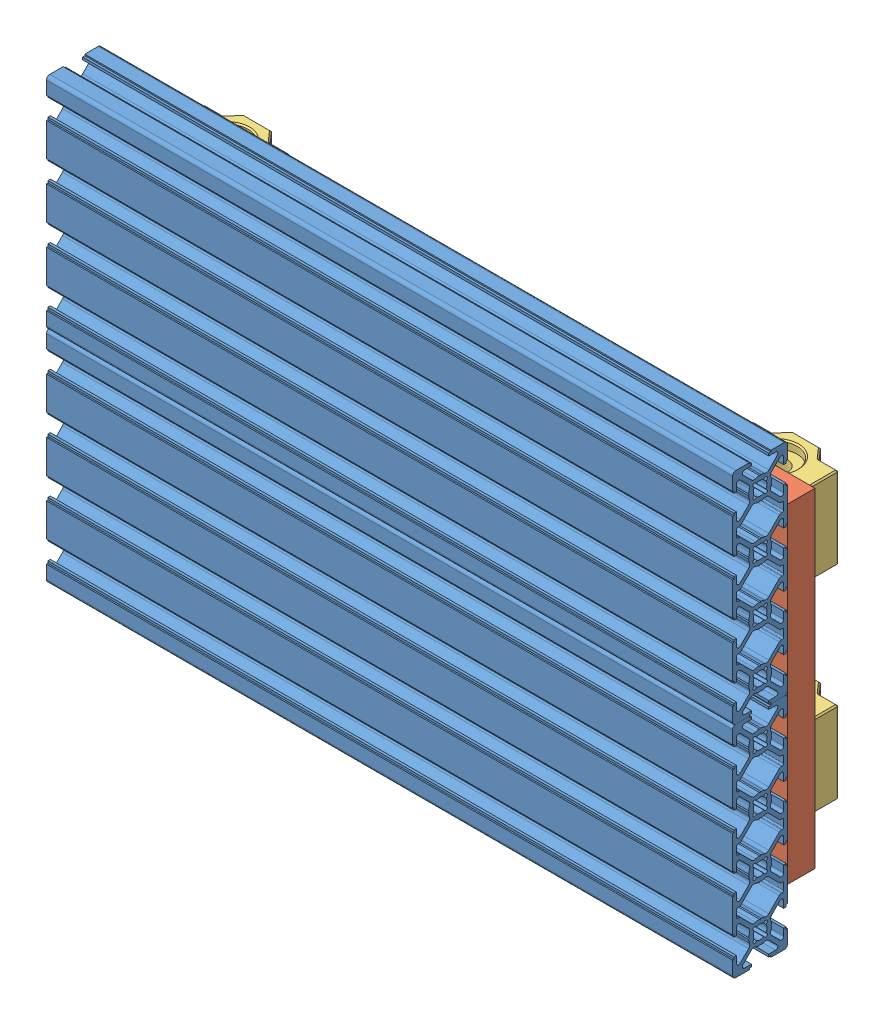
SolidWorks assembly AXIS_Y_DYNAMIC-but_bigger, configuration Default. Lengths in mm.
Overall size (250 160 52.8).
40 component instances, 6 part files, 77 mates.
Components (placement in the parent):
- 20x80x250_surface-1: 20x80x250_surface [Varsayılan] at (125 -70 0) x (0 1 0) z (1 0 0) size (80 20 250)
- 20x80x250_surface-2: 20x80x250_surface [Varsayılan] at (125 10 0) x (0 1 0) z (1 0 0) size (80 20 250)
- y_axis_elevation-1: y_axis_elevation [Default] at (100 0 -20) x (0 1 0) z (1 0 0) size (120 10 50)
- y_axis_elevation-3: y_axis_elevation [Default] at (-100 0 -20) x (0 1 0) z (1 0 0) size (120 10 50)
- linear_bearing_caged-5: linear_bearing_caged [Default] at (100 37 -31) x (1 0 0) z (0 1 0) size (34 22 30)
- linear_bearing_caged-6: linear_bearing_caged [Default] at (100 -37 -31) x (1 0 0) z (0 1 0) size (34 22 30)
- linear_bearing_caged-7: linear_bearing_caged [Default] at (-100 37 -31) x (1 0 0) z (0 1 0) size (34 22 30)
- linear_bearing_caged-8: linear_bearing_caged [Default] at (-100 -37 -31) x (1 0 0) z (0 1 0) size (34 22 30)
- socket head cap screw_din-2: socket head cap screw_din [DIN 912 M4 x 16 --- 16N] at (112 46 -10) x (0 0 -1) z (1 0 0) size (20 7 7)
- socket head cap screw_din-3: socket head cap screw_din [DIN 912 M4 x 16 --- 16N] at (88 46 -10) x (0 0 -1) z (1 0 0) size (20 7 7)
- socket head cap screw_din-4: socket head cap screw_din [DIN 912 M4 x 16 --- 16N] at (88 28 -10) x (0 0 -1) z (1 0 0) size (20 7 7)
- socket head cap screw_din-5: socket head cap screw_din [DIN 912 M4 x 16 --- 16N] at (112 28 -10) x (0 0 -1) z (1 0 0) size (20 7 7)
- socket head cap screw_din-6: socket head cap screw_din [DIN 912 M4 x 16 --- 16N] at (112 -28 -10) x (0 0 -1) z (1 0 0) size (20 7 7)
- socket head cap screw_din-7: socket head cap screw_din [DIN 912 M4 x 16 --- 16N] at (88 -28 -10) x (0 0 -1) z (1 0 0) size (20 7 7)
- socket head cap screw_din-8: socket head cap screw_din [DIN 912 M4 x 16 --- 16N] at (88 -46 -10) x (0 0 -1) z (1 0 0) size (20 7 7)
- socket head cap screw_din-9: socket head cap screw_din [DIN 912 M4 x 16 --- 16N] at (112 -46 -10) x (0 0 -1) z (1 0 0) size (20 7 7)
- socket head cap screw_din-10: socket head cap screw_din [DIN 912 M4 x 16 --- 16N] at (-112 46 -10) x (0 0 -1) z (1 0 0) size (20 7 7)
- socket head cap screw_din-11: socket head cap screw_din [DIN 912 M4 x 16 --- 16N] at (-88 46 -10) x (0 0 -1) z (1 0 0) size (20 7 7)
- socket head cap screw_din-12: socket head cap screw_din [DIN 912 M4 x 16 --- 16N] at (-88 28 -10) x (0 0 -1) z (1 0 0) size (20 7 7)
- socket head cap screw_din-13: socket head cap screw_din [DIN 912 M4 x 16 --- 16N] at (-112 28 -10) x (0 0 -1) z (1 0 0) size (20 7 7)
- socket head cap screw_din-14: socket head cap screw_din [DIN 912 M4 x 16 --- 16N] at (-88 -28 -10) x (0 0 -1) z (1 0 0) size (20 7 7)
- socket head cap screw_din-15: socket head cap screw_din [DIN 912 M4 x 16 --- 16N] at (-112 -28 -10) x (0 0 -1) z (1 0 0) size (20 7 7)
- socket head cap screw_din-16: socket head cap screw_din [DIN 912 M4 x 16 --- 16N] at (-112 -46 -10) x (0 0 -1) z (1 0 0) size (20 7 7)
- socket head cap screw_din-17: socket head cap screw_din [DIN 912 M4 x 16 --- 16N] at (-88 -46 -10) x (0 0 -1) z (1 0 0) size (20 7 7)
- socket head cap screw_din-19: socket head cap screw_din [DIN 912 M5 x 10 --- 10N] at (100 50 -20) x (0 0 1) z (-1 0 0) size (15 8.5 8.5)
- socket head cap screw_din-20: socket head cap screw_din [DIN 912 M5 x 10 --- 10N] at (100 30 -20) x (0 0 1) z (-1 0 0) size (15 8.5 8.5)
- socket head cap screw_din-21: socket head cap screw_din [DIN 912 M5 x 10 --- 10N] at (100 10 -20) x (0 0 1) z (-1 0 0) size (15 8.5 8.5)
- socket head cap screw_din-22: socket head cap screw_din [DIN 912 M5 x 10 --- 10N] at (100 -10 -20) x (0 0 1) z (-1 0 0) size (15 8.5 8.5)
- socket head cap screw_din-23: socket head cap screw_din [DIN 912 M5 x 10 --- 10N] at (100 -30 -20) x (0 0 1) z (-1 0 0) size (15 8.5 8.5)
- socket head cap screw_din-24: socket head cap screw_din [DIN 912 M5 x 10 --- 10N] at (100 -50 -20) x (0 0 1) z (-1 0 0) size (15 8.5 8.5)
- socket head cap screw_din-25: socket head cap screw_din [DIN 912 M5 x 10 --- 10N] at (-100 50 -20) x (0 0 1) z (-1 0 0) size (15 8.5 8.5)
- socket head cap screw_din-26: socket head cap screw_din [DIN 912 M5 x 10 --- 10N] at (-100 30 -20) x (0 0 1) z (-1 0 0) size (15 8.5 8.5)
- socket head cap screw_din-27: socket head cap screw_din [DIN 912 M5 x 10 --- 10N] at (-100 10 -20) x (0 0 1) z (-1 0 0) size (15 8.5 8.5)
- socket head cap screw_din-28: socket head cap screw_din [DIN 912 M5 x 10 --- 10N] at (-100 -10 -20) x (0 0 1) z (-1 0 0) size (15 8.5 8.5)
- socket head cap screw_din-29: socket head cap screw_din [DIN 912 M5 x 10 --- 10N] at (-100 -30 -20) x (0 0 1) z (-1 0 0) size (15 8.5 8.5)
- socket head cap screw_din-30: socket head cap screw_din [DIN 912 M5 x 10 --- 10N] at (-100 -50 -20) x (0 0 1) z (-1 0 0) size (15 8.5 8.5)
- SK10_rod_holder-1: SK10_rod_holder [Default] at (0 3 -30) x (1 0 0) z (0 1 0) size (42 32.8 14)
- trapezoidal_nut-1: trapezoidal_nut [Default] at (0 21 -30) x (0.995058 0 0.099296) z (0 -1 0) size (22 22 15)
- socket head cap screw_din-31: socket head cap screw_din [DIN 912 M5 x 10 --- 10N] at (16 10 -21) x (0 0 1) z (-1 0 0) size (15 8.5 8.5)
- socket head cap screw_din-32: socket head cap screw_din [DIN 912 M5 x 10 --- 10N] at (-16 10 -21) x (0 0 1) z (-1 0 0) size (15 8.5 8.5)
Mates (geometry in assembly coordinates):
- Coincident1: coincident anti-aligned: plane of 20x80x250_surface-1 through (-125 0 3.95) normal (0 1 0); plane of 20x80x250_surface-2 through (-125 0 8.8) normal (0 -1 0)
- Coincident2: coincident aligned: plane of 20x80x250_surface-1 through (-125 -13.95 10) normal (0 0 1); plane of 20x80x250_surface-2 through (-125 26.05 10) normal (0 0 1)
- Coincident3: coincident aligned: plane of 20x80x250_surface-1 through (125 -75.6787 -7.8) normal (1 0 0); plane of 20x80x250_surface-2 through (125 4.3213 -7.8) normal (1 0 0)
- Coincident4: coincident anti-aligned: plane of 20x80x250_surface-2 through (-125 53.95 -10) normal (0 0 -1); plane of y_axis_elevation-1 through (100 0 -10) normal (0 0 1)
- Coincident5: coincident aligned: plane of 20x80x250_surface-2 through (125 4.3213 -7.8) normal (1 0 0); plane of y_axis_elevation-1 through (125 60 -10) normal (1 0 0)
- Width1: width anti-aligned: plane of y_axis_elevation-1 through (125 60 -10) normal (0 1 0); plane of 20x80x250_surface-1 through (125 -60 -10) normal (0 -1 0); plane of y_axis_elevation-1 through (-125 -80 8.8) normal (0 -1 0); plane of 20x80x250_surface-2 through (-125 80 3.95) normal (0 1 0)
- Coincident6: coincident anti-aligned: plane of 20x80x250_surface-2 through (-125 53.95 -10) normal (0 0 -1); plane of y_axis_elevation-3 through (-100 0 -10) normal (0 0 1)
- Coincident7: coincident aligned: plane of 20x80x250_surface-2 through (-125 4.3213 -7.8) normal (-1 0 0); plane of y_axis_elevation-3 through (-125 60 -10) normal (-1 0 0)
- Coincident8: coincident aligned: plane of y_axis_elevation-1 through (125 60 -10) normal (0 1 0); plane of y_axis_elevation-3 through (-75 60 -10) normal (0 1 0)
- Coincident9: coincident anti-aligned: plane of y_axis_elevation-1 through (100 0 -20) normal (0 0 -1); plane of linear_bearing_caged-5 through (117 52 -20) normal (0 0 1)
- Concentric1: concentric anti-aligned: cylinder of y_axis_elevation-1 through (112 46 -20) axis (0 0 1) radius 1.5; cylinder of linear_bearing_caged-5 through (112 46 -15.7574) axis (0 0 -1) radius 1.5
- Concentric2: concentric anti-aligned: cylinder of y_axis_elevation-1 through (88 28 -20) axis (0 0 1) radius 1.5; cylinder of linear_bearing_caged-5 through (88 28 -15.7574) axis (0 0 -1) radius 1.5
- Concentric3: concentric aligned: cylinder of y_axis_elevation-1 through (112 46 -14) axis (0 0 1) radius 3.5; cylinder of socket head cap screw_din-2 through (112 46 21.75) axis (0 0 1) radius 3.5
- Coincident10: coincident anti-aligned: plane of y_axis_elevation-1 through (112 46 -14) normal (0 0 1); plane of socket head cap screw_din-2 through (112 49.5 -14) normal (0 0 -1)
- Concentric4: concentric aligned: cylinder of y_axis_elevation-1 through (88 46 -14) axis (0 0 1) radius 3.5; cylinder of socket head cap screw_din-3 through (88 46 21.75) axis (0 0 1) radius 3.5
- Coincident11: coincident anti-aligned: plane of y_axis_elevation-1 through (88 46 -14) normal (0 0 1); plane of socket head cap screw_din-3 through (88 49.5 -14) normal (0 0 -1)
- Concentric5: concentric aligned: cylinder of y_axis_elevation-1 through (88 28 -20) axis (0 0 1) radius 1.5; cylinder of socket head cap screw_din-4 through (88 28 21.75) axis (0 0 1) radius 3.5
- Coincident12: coincident anti-aligned: plane of y_axis_elevation-1 through (88 28 -14) normal (0 0 1); plane of socket head cap screw_din-4 through (88 31.5 -14) normal (0 0 -1)
- Concentric6: concentric aligned: cylinder of y_axis_elevation-1 through (112 28 -14) axis (0 0 1) radius 3.5; cylinder of socket head cap screw_din-5 through (112 28 21.75) axis (0 0 1) radius 3.5
- Coincident13: coincident anti-aligned: plane of y_axis_elevation-1 through (112 28 -14) normal (0 0 1); plane of socket head cap screw_din-5 through (112 31.5 -14) normal (0 0 -1)
- Concentric7: concentric aligned: cylinder of y_axis_elevation-1 through (112 -28 -14) axis (0 0 1) radius 3.5; cylinder of socket head cap screw_din-6 through (112 -28 21.75) axis (0 0 1) radius 3.5
- Coincident14: coincident anti-aligned: plane of y_axis_elevation-1 through (112 -28 -14) normal (0 0 1); plane of socket head cap screw_din-6 through (112 -24.5 -14) normal (0 0 -1)
- Concentric8: concentric aligned: cylinder of y_axis_elevation-1 through (88 -28 -14) axis (0 0 1) radius 3.5; cylinder of socket head cap screw_din-7 through (88 -28 21.75) axis (0 0 1) radius 3.5
- Coincident15: coincident anti-aligned: plane of y_axis_elevation-1 through (88 -28 -14) normal (0 0 1); plane of socket head cap screw_din-7 through (88 -24.5 -14) normal (0 0 -1)
- Concentric9: concentric aligned: cylinder of y_axis_elevation-1 through (88 -46 -14) axis (0 0 1) radius 3.5; cylinder of socket head cap screw_din-8 through (88 -46 21.75) axis (0 0 1) radius 3.5
- Coincident16: coincident anti-aligned: plane of y_axis_elevation-1 through (88 -46 -14) normal (0 0 1); plane of socket head cap screw_din-8 through (88 -42.5 -14) normal (0 0 -1)
- Concentric10: concentric aligned: cylinder of y_axis_elevation-1 through (112 -46 -14) axis (0 0 1) radius 3.5; cylinder of socket head cap screw_din-9 through (112 -46 21.75) axis (0 0 1) radius 3.5
- Coincident17: coincident anti-aligned: plane of y_axis_elevation-1 through (112 -46 -14) normal (0 0 1); plane of socket head cap screw_din-9 through (112 -42.5 -14) normal (0 0 -1)
- Concentric11: concentric aligned: cylinder of y_axis_elevation-3 through (-112 46 -20) axis (0 0 1) radius 1.5; cylinder of socket head cap screw_din-10 through (-112 46 21.75) axis (0 0 1) radius 3.5
- Coincident18: coincident anti-aligned: plane of y_axis_elevation-3 through (-112 46 -14) normal (0 0 1); plane of socket head cap screw_din-10 through (-112 49.5 -14) normal (0 0 -1)
- Concentric12: concentric aligned: cylinder of y_axis_elevation-3 through (-88 46 -14) axis (0 0 1) radius 3.5; cylinder of socket head cap screw_din-11 through (-88 46 21.75) axis (0 0 1) radius 3.5
- Coincident19: coincident anti-aligned: plane of y_axis_elevation-3 through (-88 46 -14) normal (0 0 1); plane of socket head cap screw_din-11 through (-88 49.5 -14) normal (0 0 -1)
- Concentric13: concentric aligned: cylinder of y_axis_elevation-3 through (-88 28 -20) axis (0 0 1) radius 1.5; cylinder of socket head cap screw_din-12 through (-88 28 21.75) axis (0 0 1) radius 3.5
- Coincident20: coincident anti-aligned: plane of y_axis_elevation-3 through (-88 28 -14) normal (0 0 1); plane of socket head cap screw_din-12 through (-88 31.5 -14) normal (0 0 -1)
- Concentric14: concentric aligned: cylinder of y_axis_elevation-3 through (-112 28 -20) axis (0 0 1) radius 1.5; cylinder of socket head cap screw_din-13 through (-112 28 21.75) axis (0 0 1) radius 3.5
- Coincident21: coincident anti-aligned: plane of y_axis_elevation-3 through (-112 28 -14) normal (0 0 1); plane of socket head cap screw_din-13 through (-112 31.5 -14) normal (0 0 -1)
- Concentric15: concentric aligned: cylinder of y_axis_elevation-3 through (-88 -28 -20) axis (0 0 1) radius 1.5; cylinder of socket head cap screw_din-14 through (-88 -28 21.75) axis (0 0 1) radius 3.5
- Coincident22: coincident anti-aligned: plane of y_axis_elevation-3 through (-88 -28 -14) normal (0 0 1); plane of socket head cap screw_din-14 through (-88 -24.5 -14) normal (0 0 -1)
- Concentric16: concentric aligned: cylinder of y_axis_elevation-3 through (-112 -28 -20) axis (0 0 1) radius 1.5; cylinder of socket head cap screw_din-15 through (-112 -28 21.75) axis (0 0 1) radius 3.5
- Coincident23: coincident anti-aligned: plane of y_axis_elevation-3 through (-112 -28 -14) normal (0 0 1); plane of socket head cap screw_din-15 through (-112 -24.5 -14) normal (0 0 -1)
- Concentric17: concentric aligned: cylinder of y_axis_elevation-3 through (-112 -46 -14) axis (0 0 1) radius 3.5; cylinder of socket head cap screw_din-16 through (-112 -46 21.75) axis (0 0 1) radius 3.5
- Coincident24: coincident anti-aligned: plane of y_axis_elevation-3 through (-112 -46 -14) normal (0 0 1); plane of socket head cap screw_din-16 through (-112 -42.5 -14) normal (0 0 -1)
- Concentric18: concentric aligned: cylinder of y_axis_elevation-3 through (-88 -46 -14) axis (0 0 1) radius 3.5; cylinder of socket head cap screw_din-17 through (-88 -46 21.75) axis (0 0 1) radius 3.5
- Coincident25: coincident anti-aligned: plane of y_axis_elevation-3 through (-88 -46 -14) normal (0 0 1); plane of socket head cap screw_din-17 through (-88 -42.5 -14) normal (0 0 -1)
- Concentric19: concentric aligned: cylinder of y_axis_elevation-1 through (100 50 -15) axis (0 0 -1) radius 4.3; cylinder of socket head cap screw_din-19 through (100 50 -51.75) axis (0 0 -1) radius 4.25
- Coincident26: coincident anti-aligned: plane of y_axis_elevation-1 through (100 50 -15) normal (0 0 -1); plane of socket head cap screw_din-19 through (100 54.25 -15) normal (0 0 1)
- Concentric20: concentric aligned: cylinder of y_axis_elevation-1 through (100 30 -15) axis (0 0 -1) radius 4.3; cylinder of socket head cap screw_din-20 through (100 30 -51.75) axis (0 0 -1) radius 4.25
- Coincident27: coincident anti-aligned: plane of y_axis_elevation-1 through (100 30 -15) normal (0 0 -1); plane of socket head cap screw_din-20 through (100 34.25 -15) normal (0 0 1)
- Concentric21: concentric aligned: cylinder of y_axis_elevation-1 through (100 10 -15) axis (0 0 -1) radius 4.3; cylinder of socket head cap screw_din-21 through (100 10 -51.75) axis (0 0 -1) radius 4.25
- Coincident28: coincident anti-aligned: plane of y_axis_elevation-1 through (100 10 -15) normal (0 0 -1); plane of socket head cap screw_din-21 through (100 14.25 -15) normal (0 0 1)
- Concentric22: concentric aligned: cylinder of y_axis_elevation-1 through (100 -10 -15) axis (0 0 -1) radius 4.3; cylinder of socket head cap screw_din-22 through (100 -10 -51.75) axis (0 0 -1) radius 4.25
- Coincident29: coincident anti-aligned: plane of y_axis_elevation-1 through (100 -10 -15) normal (0 0 -1); plane of socket head cap screw_din-22 through (100 -5.75 -15) normal (0 0 1)
- Concentric23: concentric aligned: cylinder of y_axis_elevation-1 through (100 -30 -15) axis (0 0 -1) radius 4.3; cylinder of socket head cap screw_din-23 through (100 -30 -51.75) axis (0 0 -1) radius 4.25
- Coincident30: coincident anti-aligned: plane of y_axis_elevation-1 through (100 -30 -15) normal (0 0 -1); plane of socket head cap screw_din-23 through (100 -25.75 -15) normal (0 0 1)
- Concentric24: concentric aligned: cylinder of y_axis_elevation-1 through (100 -50 -15) axis (0 0 -1) radius 4.3; cylinder of socket head cap screw_din-24 through (100 -50 -51.75) axis (0 0 -1) radius 4.25
- Coincident31: coincident anti-aligned: plane of y_axis_elevation-1 through (100 -50 -15) normal (0 0 -1); plane of socket head cap screw_din-24 through (100 -45.75 -15) normal (0 0 1)
- Concentric25: concentric aligned: cylinder of y_axis_elevation-3 through (-100 50 -15) axis (0 0 -1) radius 4.3; cylinder of socket head cap screw_din-25 through (-100 50 -51.75) axis (0 0 -1) radius 4.25
- Coincident32: coincident anti-aligned: plane of y_axis_elevation-3 through (-100 50 -15) normal (0 0 -1); plane of socket head cap screw_din-25 through (-100 54.25 -15) normal (0 0 1)
- Concentric26: concentric aligned: cylinder of y_axis_elevation-3 through (-100 30 -15) axis (0 0 -1) radius 4.3; cylinder of socket head cap screw_din-26 through (-100 30 -51.75) axis (0 0 -1) radius 4.25
- Coincident33: coincident anti-aligned: plane of y_axis_elevation-3 through (-100 30 -15) normal (0 0 -1); plane of socket head cap screw_din-26 through (-100 34.25 -15) normal (0 0 1)
- Concentric27: concentric aligned: cylinder of y_axis_elevation-3 through (-100 10 -15) axis (0 0 -1) radius 4.3; cylinder of socket head cap screw_din-27 through (-100 10 -51.75) axis (0 0 -1) radius 4.25
- Coincident34: coincident anti-aligned: plane of y_axis_elevation-3 through (-100 10 -15) normal (0 0 -1); plane of socket head cap screw_din-27 through (-100 14.25 -15) normal (0 0 1)
- Concentric28: concentric aligned: cylinder of y_axis_elevation-3 through (-100 -10 -15) axis (0 0 -1) radius 4.3; cylinder of socket head cap screw_din-28 through (-100 -10 -51.75) axis (0 0 -1) radius 4.25
- Coincident35: coincident anti-aligned: plane of y_axis_elevation-3 through (-100 -10 -15) normal (0 0 -1); plane of socket head cap screw_din-28 through (-100 -5.75 -15) normal (0 0 1)
- Concentric29: concentric aligned: cylinder of y_axis_elevation-3 through (-100 -30 -10) axis (0 0 -1) radius 2.5; cylinder of socket head cap screw_din-29 through (-100 -30 -51.75) axis (0 0 -1) radius 4.25
- Coincident36: coincident anti-aligned: plane of y_axis_elevation-3 through (-100 -30 -15) normal (0 0 -1); plane of socket head cap screw_din-29 through (-100 -25.75 -15) normal (0 0 1)
- Concentric30: concentric aligned: cylinder of y_axis_elevation-3 through (-100 -50 -10) axis (0 0 -1) radius 2.5; cylinder of socket head cap screw_din-30 through (-100 -50 -51.75) axis (0 0 -1) radius 4.25
- Coincident37: coincident anti-aligned: plane of y_axis_elevation-3 through (-100 -50 -15) normal (0 0 -1); plane of socket head cap screw_din-30 through (-100 -45.75 -15) normal (0 0 1)
- Coincident38: coincident anti-aligned: plane of SK10_rod_holder-1 through (0 17 -30) normal (0 1 0); plane of trapezoidal_nut-1 through (0 17 -30) normal (0 -1 0)
- Concentric31: concentric anti-aligned: cylinder of SK10_rod_holder-1 through (0 17 -30) axis (0 -1 0) radius 5; cylinder of trapezoidal_nut-1 through (0 6 -30) axis (0 1 0) radius 5.15
- Coincident40: coincident anti-aligned: plane of 20x80x250_surface-2 through (-125 13.95 -10) normal (0 0 -1); plane of SK10_rod_holder-1 through (-21 17 -10) normal (0 0 1)
- Width2: width aligned: plane of SK10_rod_holder-1 through (0 17 -30) normal (0 1 0); plane of 20x80x250_surface-2 through (0 3 -30) normal (0 -1 0); plane of SK10_rod_holder-1 through (-125 13.1768 -4.1667) normal (0 -0.707107 -0.707107); plane of 20x80x250_surface-2 through (-125 3.7556 -7.2343) normal (0 0.707107 -0.707107)
- Width3: width anti-aligned: plane of SK10_rod_holder-1 through (-9 17 -42.8) normal (-1 0 0); plane of y_axis_elevation-3 through (9 17 -42.8) normal (1 0 0); plane of SK10_rod_holder-1 through (-75 60 -10) normal (1 0 0); plane of y_axis_elevation-1 through (75 60 -10) normal (-1 0 0)
- Coincident41: coincident anti-aligned: plane of SK10_rod_holder-1 through (9 17 -16) normal (0 0 -1); plane of socket head cap screw_din-31 through (16 14.25 -16) normal (0 0 1)
- Coincident42: coincident anti-aligned: plane of SK10_rod_holder-1 through (-9 17 -16) normal (0 0 -1); plane of socket head cap screw_din-32 through (-16 14.25 -16) normal (0 0 1)
- Concentric32: concentric aligned: cylinder of SK10_rod_holder-1 through (16 10 -10) axis (0 0 -1) radius 2.75; cylinder of socket head cap screw_din-31 through (16 10 -52.75) axis (0 0 -1) radius 2.5
- Concentric33: concentric aligned: cylinder of SK10_rod_holder-1 through (-16 10 -10) axis (0 0 -1) radius 2.75; cylinder of socket head cap screw_din-32 through (-16 10 -52.75) axis (0 0 -1) radius 2.5
